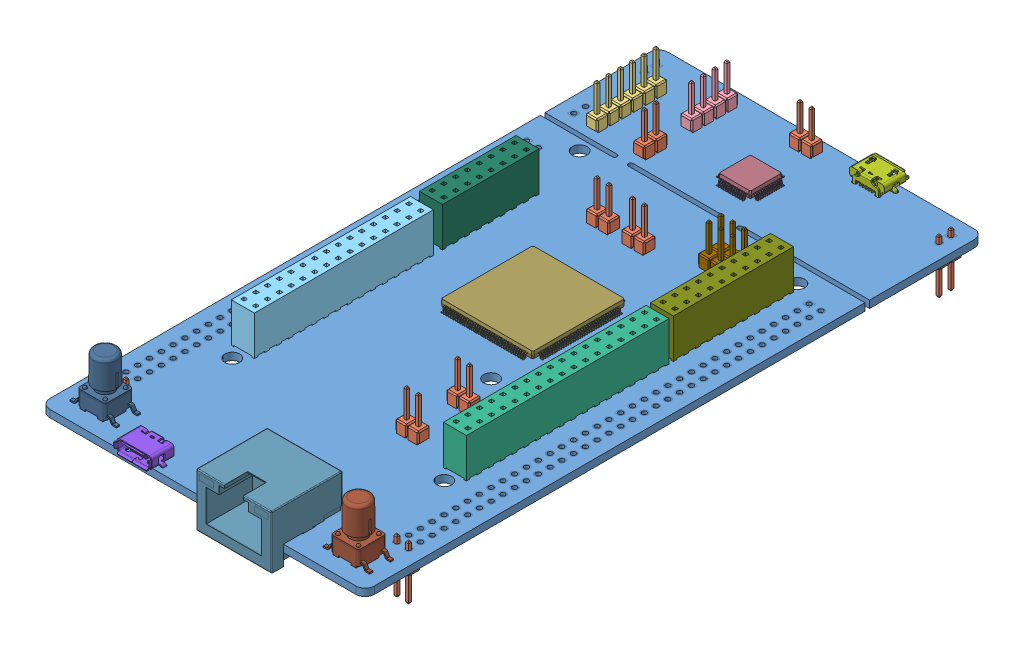
SolidWorks assembly NUCLEO-F429ZI--3DModel-STEP-565441, configuration Default. Lengths in mm.
Overall size (70 20.82 136.99).
25 component instances, 16 part files, 0 mates.
Components (placement in the parent):
- NUCLEO-F429ZI board-1: NUCLEO-F429ZI board [Default] at origin size (70 1.58 133.34)
- jp1-1: jp1 [Default] at (-1.27 1.58 -63.37) size (5.08 11.6 2.54)
- jp1-2: jp1 [Default] at (-16.55 1.58 -45.09) x (0 0 -1) z (1 0 0) size (5.08 11.6 2.54)
- cn6-1: cn6 [Default] at (-26.75 1.58 -45.07) x (0 0 -1) z (1 0 0) size (15.24 11.6 2.54)
- cn4-1: cn4 [Default] at (-16.55 1.58 -55.25) x (0 0 -1) z (1 0 0) size (10.16 11.6 2.54)
- cn9-1: cn9 [Default] at (-22.86 1.58 15.87) x (0 0 -1) z (1 0 0) size (38.61 13.34 4.95)
- cn10-1: cn10 [Default] at (22.86 1.58 13.33) x (0 0 -1) z (1 0 0) size (43.69 13.34 4.95)
- jp1-3: jp1 [Default] at (-31.75 0 -62.87) x (0 0 1) z (1 0 0) size (5.08 11.6 2.54)
- jp1-4: jp1 [Default] at (31.75 0 -60.33) x (0 0 -1) z (-1 0 0) size (5.08 11.6 2.54)
- cn1-1: cn1 [Default] at (13.9 2.805 -64.97) x (-1 0 0) z (0 0 -1) size (8.2 3.3 5.4)
- cn13-1: cn13 [Default] at (-15.6 1.88 63.62) x (-1 0 0) z (0 0 -1) size (8.66 3.36 5.9)
- jp3-1: jp3 [Default] at (11.45 1.58 -33.61) size (7.62 11.6 5.08)
- jp1-5: jp1 [Default] at (-8.91 1.58 -27.27) size (5.08 11.6 2.54)
- jp1-6: jp1 [Default] at (-1.27 1.58 -27.27) size (5.08 11.6 2.54)
- jp1-7: jp1 [Default] at (-29.21 0 54.03) x (-1 0 0) z (0 0 1) size (5.08 11.6 2.54)
- jp1-8: jp1 [Default] at (31.75 0 54.03) x (-1 0 0) z (0 0 1) size (5.08 11.6 2.54)
- b1-1: b1 [Default] at (-27.3 1.58 60.4) x (0 0 -1) z (1 0 0) size (6 10.7 10)
- b2-1: b2 [Default] at (27.3 1.58 60.4) x (0 0 -1) z (1 0 0) size (6 10.7 10)
- jp1-9: jp1 [Default] at (9.79 1.58 21.49) size (5.08 11.6 2.54)
- jp1-10: jp1 [Default] at (9.79 1.58 32.49) size (5.08 11.6 2.54)
- STM32lqfp144-1: STM32lqfp144 [Default] at (0 2.4349 -4.5) size (21.95 1.58 21.95)
- STM32F103CBT6-1: STM32F103CBT6 [Default] at (0 2.4349 -51.4) size (9 1.6 9)
- lan-1: lan [Default] at (9.3 3.13 69.27) size (16.2 11.5 15.3)
- cn8-1: cn8 [Default] at (-22.86 1.58 -15.8) x (0 0 -1) z (1 0 0) size (20.83 13.33 4.95)
- cn7-1: cn7 [Default] at (22.86 1.58 -22.42) x (0 0 -1) z (1 0 0) size (25.91 13.33 4.95)
